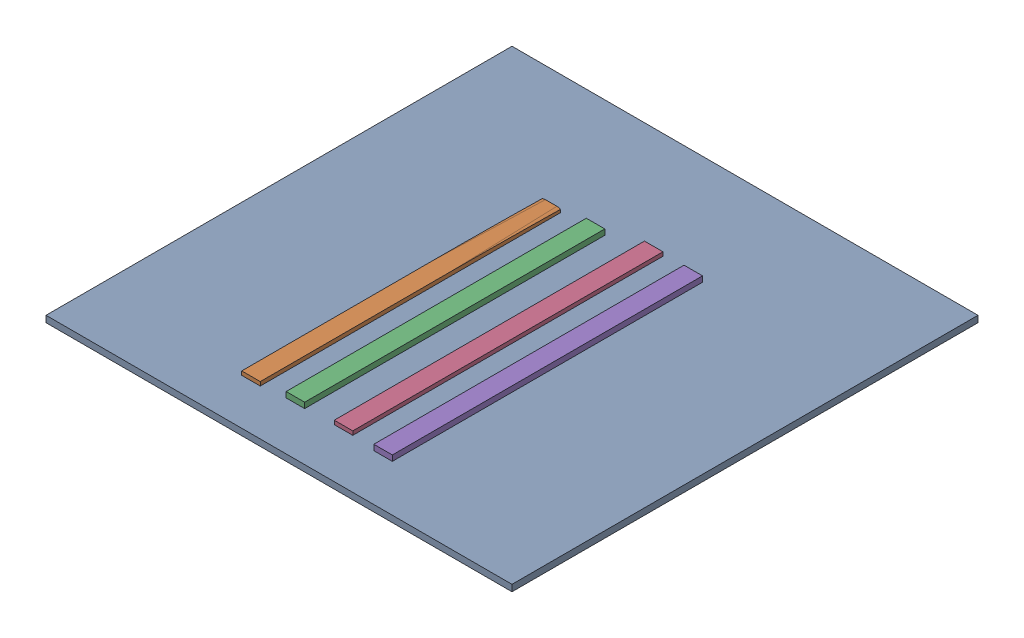
SolidWorks assembly revised, configuration Default. Lengths in mm.
Overall size (914.4 23.62 914.4).
5 component instances, 5 part files, 7 mates.
Components (placement in the parent):
- Cut Area-1: Cut Area [Default] at origin size (914.4 12.7 914.4)
- Fuselage Mold-top-BackTop-1: Fuselage Mold-top-BackTop [Default] at (312.3464 -29.591 494.2987) size (36.32 20.32 588.97)
- Fuselage Mold-top-BackBottom-1: Fuselage Mold-top-BackBottom [Default] at (394.2522 -5.969 489.0696) size (36.32 23.62 588.97)
- Fuselage Mold-top-FrontTop-1: Fuselage Mold-top-FrontTop [Default] at (486.8867 -29.591 -121.4196) size (36.32 20.32 608.71)
- Fuselage Mold-top-FrontBottom-1: Fuselage Mold-top-FrontBottom [Default] at (569.9038 -5.969 -116.0025) size (36.32 23.62 608.71)
Mates (geometry in assembly coordinates):
- Coincident1: coincident: point of Cut Area-1
- Parallel1: parallel aligned: plane of Cut Area-1 through (0 12.7 0) normal (0 1 0)
- Parallel2: parallel anti-aligned: plane of Cut Area-1 through (0 12.7 0) normal (-1 0 0)
- Distance1: distance = 0 mm aligned: plane of Fuselage Mold-top-BackTop-1 through (312.3464 0 494.2987) normal (0 -1 0); plane of Cut Area-1 through (0 0 0) normal (0 -1 0)
- Distance2: distance = 0 mm aligned: plane of Fuselage Mold-top-BackBottom-1 through (394.2522 0 489.0696) normal (0 -1 0); plane of Cut Area-1 through (0 0 0) normal (0 -1 0)
- Distance3: distance = 0 mm aligned: plane of Fuselage Mold-top-FrontTop-1 through (486.8867 0 -121.4196) normal (0 -1 0); plane of Cut Area-1 through (0 0 0) normal (0 -1 0)
- Distance4: distance = 0 mm aligned: plane of Fuselage Mold-top-FrontBottom-1 through (569.9038 0 -116.0025) normal (0 -1 0); plane of Cut Area-1 through (0 0 0) normal (0 -1 0)
